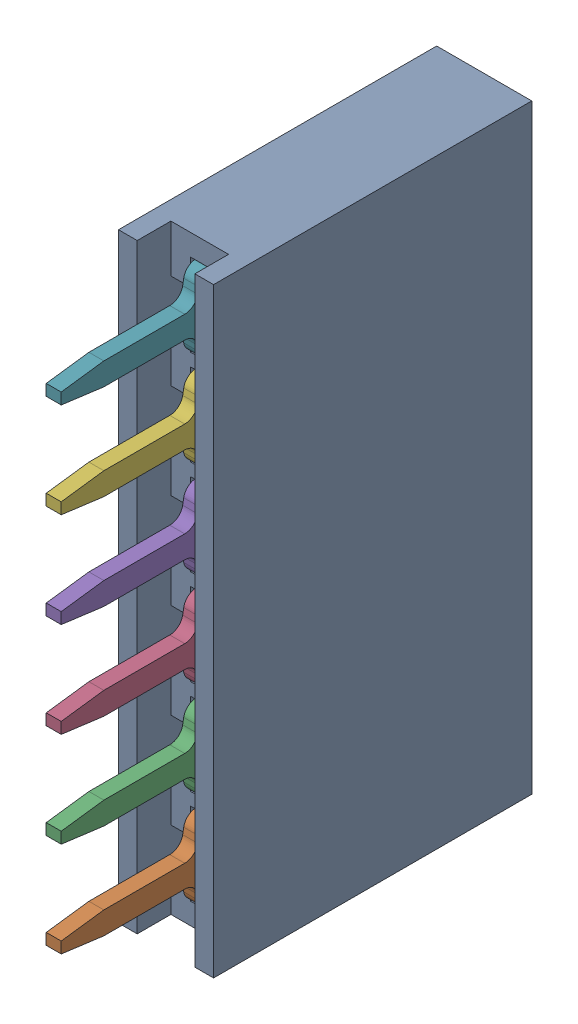
SolidWorks assembly H1_1.step, configuration Default. Lengths in mm.
Overall size (2.54 16.04 11.5).
8 component instances, 2 part files, 0 mates.
Components (placement in the parent):
- DS1023-1x6SF11_1.step-11: DS1023-1x6SF11_1.step [Default] at (486.5324 321.8178 -1.647) x (0 1 0) z (0 0 -1) size (16.04 2.54 11.5)
  - body_3.step-32: body_3.step [Default] at origin size (16.04 2.54 8.5)
  - contact_1.step-195: contact_1.step [Default] at origin size (2.3 0.4 9)
  - contact_1.step-196: contact_1.step [Default] at (2.54 0 0) size (2.3 0.4 9)
  - contact_1.step-199: contact_1.step [Default] at (5.08 0 0) size (2.3 0.4 9)
  - contact_1.step-200: contact_1.step [Default] at (7.62 0 0) size (2.3 0.4 9)
  - contact_1.step-201: contact_1.step [Default] at (10.16 0 0) size (2.3 0.4 9)
  - contact_1.step-202: contact_1.step [Default] at (12.7 0 0) size (2.3 0.4 9)
